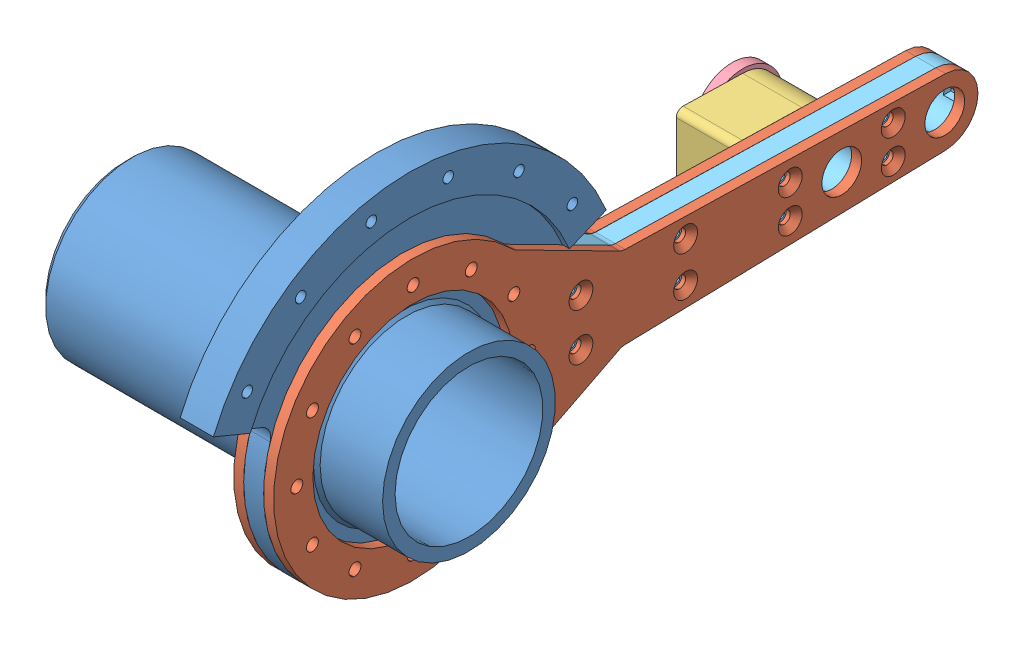
SolidWorks assembly hip-hind-new-left-2012-09-05, configuration Default. Lengths in mm.
Overall size (51.7 93.39 184.65).
7 component instances, 6 part files, 16 mates.
Components (placement in the parent):
- abs-hip-front-2012-11-20-1: abs-hip-front-2012-11-20 [Default] at (15.6334 7.6716 -13.4615) size (51.7 53 129.22)
- Hip_gear-1: Hip_gear [Default] at (14.6334 7.6716 -13.4615) x (1 0 0) z (0 -0.382683 -0.92388) size (9 71.48 71.48)
- carbon-plate-hip-hind-1: carbon-plate-hip-hind [Default] at (12.6334 7.6716 -13.4615) x (0 0 -1) z (1 0 0) size (106 42 1.5)
- carbon-plate-hip-hind-2: carbon-plate-hip-hind [Default] at (17.1334 7.6716 -13.4615) x (0 0 -1) z (1 0 0) size (106 42 1.5)
- distancepiece_legsprings_011112_Mill_Pom-1: distancepiece_legsprings_011112_Mill_Pom [Default] at (8.1834 7.6716 -77.9615) x (0 -1 0) z (-1 0 0) size (11.24 15.4 8.9)
- Washer-d6p5-12-1: Washer-d6p5-12 [Défaut] at (2.9334 7.6716 -77.9615) x (0 0 1) z (-1 0 0) size (12 12 1.6)
- Pom-plat-hip-hind-04-03-13-1: Pom-plat-hip-hind-04-03-13 [Default] at (14.1334 7.6716 -13.4615) x (0 0 -1) z (1 0 0) size (68.27 23.38 3)
Mates (geometry in assembly coordinates):
- Concentric1: concentric anti-aligned: cylinder of abs-hip-front-2012-11-20-1 through (15.6334 7.6716 -13.4615) axis (-1 0 0) radius 32; cylinder of Hip_gear-1 through (13.1334 7.6716 -13.4615) axis (1 0 0) radius 32
- Coincident1: coincident anti-aligned: plane of abs-hip-front-2012-11-20-1 through (13.1334 19.9175 16.1027) normal (-1 0 0); plane of Hip_gear-1 through (13.1334 31.6925 -23.4113) normal (1 0 0)
- Coincident2: coincident anti-aligned: plane of abs-hip-front-2012-11-20-1 through (14.1334 12.6465 -1.4511) normal (-1 0 0); plane of carbon-plate-hip-hind-1 through (14.1334 7.6716 -93.4615) normal (1 0 0)
- Concentric3: concentric aligned: cylinder of abs-hip-front-2012-11-20-1 through (15.6334 7.6716 -13.4615) axis (-1 0 0) radius 21; cylinder of carbon-plate-hip-hind-1 through (14.1334 7.6716 -13.4615) axis (-1 0 0) radius 15.1
- Concentric4: concentric aligned: cylinder of abs-hip-front-2012-11-20-1 through (15.6334 7.6716 -13.4615) axis (-1 0 0) radius 13; cylinder of carbon-plate-hip-hind-2 through (18.6334 7.6716 -13.4615) axis (-1 0 0) radius 15.1
- Coincident3: coincident anti-aligned: plane of abs-hip-front-2012-11-20-1 through (17.1334 12.6465 -1.4511) normal (1 0 0); plane of carbon-plate-hip-hind-2 through (17.1334 7.6716 -93.4615) normal (-1 0 0)
- Concentric5: concentric aligned: cylinder of carbon-plate-hip-hind-1 through (14.1334 7.6716 -93.4615) axis (-1 0 0) radius 3; cylinder of carbon-plate-hip-hind-2 through (18.6334 7.6716 -93.4615) axis (-1 0 0) radius 3
- Concentric8: concentric anti-aligned: cylinder of abs-hip-front-2012-11-20-1 through (17.1334 23.2533 10.9969) axis (1 0 0) radius 0.8; cylinder of Hip_gear-1 through (10.1334 23.2533 10.9969) axis (-1 0 0) radius 1.2
- Concentric10: concentric anti-aligned: cylinder of abs-hip-front-2012-11-20-1 through (14.1334 7.6716 -30.9615) axis (-1 0 0) radius 0.625; cylinder of carbon-plate-hip-hind-1 through (14.1334 7.6716 -30.9615) axis (1 0 0) radius 0.9
- Coïncidente1: coincident anti-aligned: plane of carbon-plate-hip-hind-1 through (12.6334 7.6716 -93.4615) normal (-1 0 0); plane of distancepiece_legsprings_011112_Mill_Pom-1 through (12.6334 7.6716 -77.9615) normal (1 0 0)
- Coaxiale3: concentric aligned: cylinder of carbon-plate-hip-hind-1 through (14.1334 5.1716 -70.2115) axis (1 0 0) radius 0.9; cylinder of distancepiece_legsprings_011112_Mill_Pom-1 through (12.6334 5.1716 -70.2115) axis (1 0 0) radius 0.625
- Coïncidente2: coincident anti-aligned: plane of distancepiece_legsprings_011112_Mill_Pom-1 through (3.7334 7.6716 -77.9615) normal (-1 0 0); plane of Washer-d6p5-12-1 through (3.7334 7.6716 -77.9615) normal (1 0 0)
- Coaxiale4: concentric anti-aligned: cylinder of distancepiece_legsprings_011112_Mill_Pom-1 through (12.6334 7.6716 -77.9615) axis (-1 0 0) radius 3.05; cylinder of Washer-d6p5-12-1 through (2.1334 7.6716 -77.9615) axis (1 0 0) radius 3.25
- Coïncidente3: coincident anti-aligned: plane of carbon-plate-hip-hind-1 through (14.1334 7.6716 -93.4615) normal (1 0 0); plane of Pom-plat-hip-hind-04-03-13-1 through (14.1334 7.6716 -93.4615) normal (-1 0 0)
- Coaxiale5: concentric aligned: cylinder of carbon-plate-hip-hind-1 through (14.1334 7.6716 -93.4615) axis (-1 0 0) radius 3; cylinder of Pom-plat-hip-hind-04-03-13-1 through (17.1334 7.6716 -93.4615) axis (-1 0 0) radius 3
- Coaxiale6: concentric aligned: cylinder of carbon-plate-hip-hind-1 through (14.1334 7.6716 -77.9615) axis (-1 0 0) radius 3; cylinder of Pom-plat-hip-hind-04-03-13-1 through (17.1334 7.6716 -77.9615) axis (-1 0 0) radius 3
